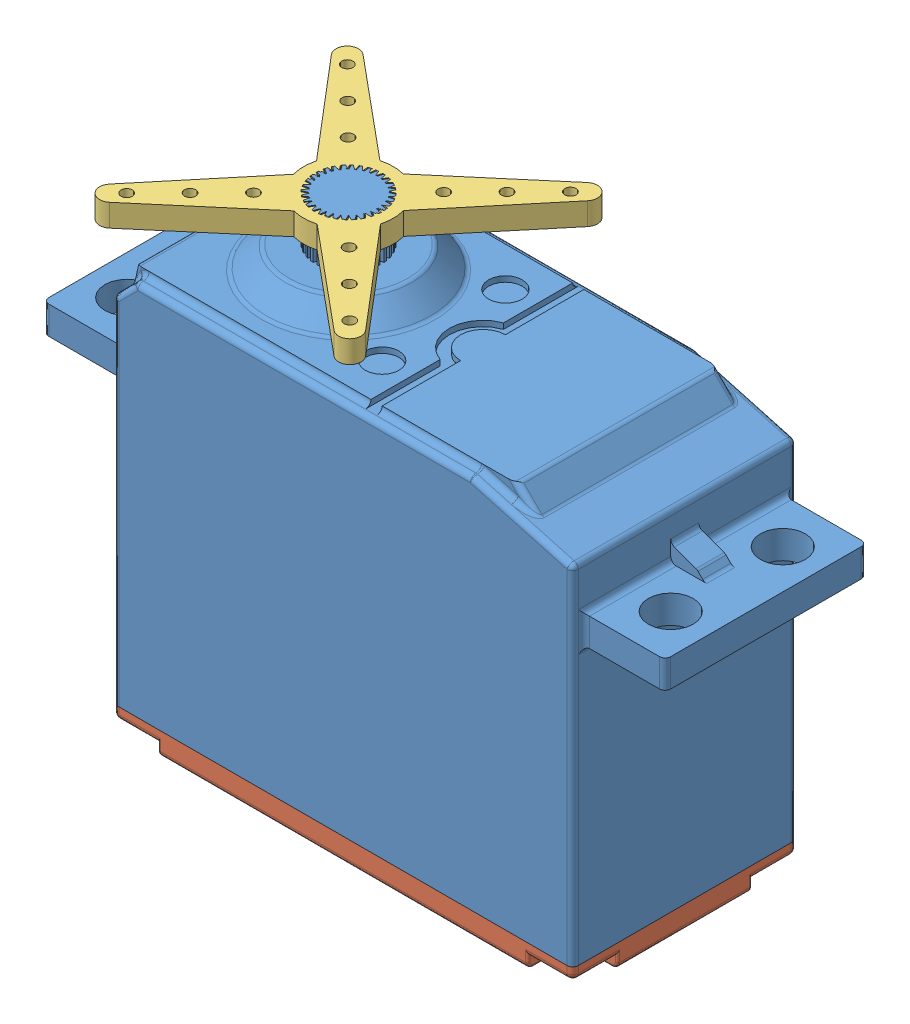
SolidWorks assembly FUTABA_S3003, configuration Default. Lengths in mm.
Overall size (59.88 42.1 45.25).
3 component instances, 3 part files, 5 mates.
Components (placement in the parent):
- corpo-1: corpo [Default] at origin size (55.5 40 20)
- tampa-1: tampa [Default] x (-1 0 0) z (0 -1 0) size (43 20 2.1)
- FUTM2040-1: FUTM2040 [Default] at (-9.5 38 0) x (-0.703172 0 0.71102) z (0 1 0) size (32 32 2)
Mates (geometry in assembly coordinates):
- Coincident1: coincident aligned: plane of corpo-1 through (-9.5 40 0) normal (0 1 0); plane of FUTM2040-1 through (-9.5 40 0) normal (0 1 0)
- Concentric1: concentric anti-aligned: circle of corpo-1; circle of FUTM2040-1
- Coincident3: coincident aligned: plane of corpo-1 through (-20.5 34 10) normal (0 0 1); plane of tampa-1 through (20.5 -2.1 10) normal (0 0 1)
- Coincident4: coincident anti-aligned: plane of corpo-1 through (-20.5 0 10) normal (0 -1 0); plane of tampa-1 through (20.5 0 10) normal (0 1 0)
- Coincident5: coincident aligned: plane of corpo-1 through (-20.5 34 -10) normal (-1 0 0); plane of tampa-1 through (-20.5 -2.1 -10) normal (-1 0 0)
